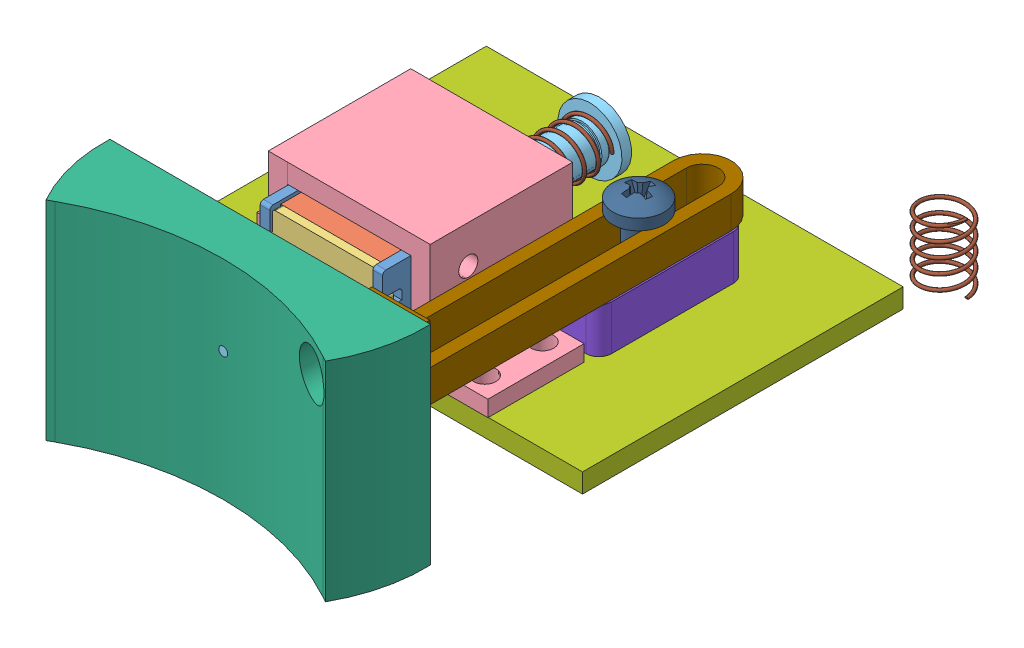
SolidWorks assembly solenoid assembly 2, configuration Default. Lengths in mm.
Overall size (70.84 33.54 84.51).
14 component instances, 11 part files, 14 mates.
Components (placement in the parent):
- solenoid assembly-1: solenoid assembly [Default] at (10.7886 26.9841 31.6501) size (43.25 18.9 29.35)
  - Solenoid frame-1: Solenoid frame [Default] at (12.0021 -4.2273 1.9322) size (19.1 15.9 29.35)
  - top face-2: top face [Default] at (3.3021 3.2227 1.0822) size (17.4 1.5 26.15)
  - top face-3: top face [Default] at (3.3021 -10.1773 1.0822) size (17.4 1.5 26.15)
  - Solenoid front frame-3: Solenoid front frame [Default] at (3.9521 -4.2292 15.4572) size (19.1 14.9 1.3)
  - mount solenoid-1: mount solenoid [Default] at (-5.7478 -4.2273 0.3372) x (0 0 1) z (-1 0 0) size (22.27 18.9 43.25)
- cylinder-1: cylinder [Default] at (15.8918 23.938 22.0581) x (0 0 1) z (-0.688665 0.72508 0) size (58.68 10 10)
- kicker-1: kicker [Default] at (14.7407 22.8447 56.3756) x (-1 0 0) z (0 1 0) size (50.03 13.18 32.5)
- testing board-1: testing board [Default] at (18.4884 11.8068 18.042) size (65 3 50)
- slider pole-2: slider pole [Default] at (32.2907 14.8068 15.298) size (10 7 23)
- slider-1: slider [Default] at (32.5307 21.8047 48.9015) x (0 0 -1) z (1 0 0) size (54.1 11.45 9)
- pan cross head screw_as-1: pan cross head screw_as [AS-NZS 1427 PC- M4 x 25-N] at (31.9907 29.9047 15.298) x (0 -1 0) z (-0.154373 0 0.988013) size (28.02 8 8)
- spring-1: spring [Default] at (14.7407 22.8447 16.5076) x (0.999856 -0.016979 0) z (0.016979 0.999856 0) size (7.76 11.37 8.66)
- spring-2: spring [Default] at (52.8173 13.6068 -11.5001) size (7.76 11.37 8.66)
Mates (geometry in assembly coordinates):
- Concentric1: concentric aligned: cylinder of solenoid assembly-1/Solenoid frame-1 through (14.7407 22.8447 19.6574) axis (0 0 -1) radius 3.175; cylinder of cylinder-1 through (14.7407 22.8447 5.6381) axis (0 0 -1) radius 3.175
- Concentric3: concentric aligned: cylinder of cylinder-1 through (14.7407 22.8447 42.614) axis (0 0 -1) radius 0.75; cylinder of kicker-1 through (14.7407 22.8447 68.6814) axis (0 0 -1) radius 0.7
- Parallel1: parallel anti-aligned: line of solenoid assembly-1/mount solenoid-1 through (5.0407 33.7068 43.0974) axis (1 0 0); line of kicker-1 through (39.7407 35.3447 55.5015) axis (-1 0 0)
- Tangent1: tangent anti-aligned: plane of cylinder-1 through (14.7407 22.8447 62.814) normal (0 0 1); cylinder of kicker-1 through (14.7407 10.3447 106.1689) axis (0 1 0) radius 43.3549
- Coincident4: coincident anti-aligned: plane of solenoid assembly-1/mount solenoid-1 through (27.2907 14.8068 43.0974) normal (0 -1 0); plane of testing board-1 through (18.4884 14.8068 18.042) normal (0 1 0)
- Coincident5: coincident anti-aligned: plane of testing board-1 through (18.4884 14.8068 18.042) normal (0 1 0); plane of slider pole-2 through (32.2907 14.8068 15.298) normal (0 -1 0)
- Coincident6: coincident anti-aligned: plane of solenoid assembly-1/mount solenoid-1 through (27.2907 22.7568 31.9874) normal (1 0 0); plane of slider pole-2 through (27.2907 21.8068 3.798) normal (-1 0 0)
- Concentric6: concentric anti-aligned: cylinder of kicker-1 through (32.5307 30.6047 55.5015) axis (0 0 1) radius 2; cylinder of slider-1 through (32.5307 30.6047 57.9015) axis (0 0 -1) radius 1.75
- Coincident7: coincident anti-aligned: plane of kicker-1 through (39.7407 35.3447 55.5015) normal (0 0 -1); plane of slider-1 through (28.0307 21.8047 55.5015) normal (0 0 1)
- Parallel2: parallel anti-aligned: line of kicker-1 through (39.7407 35.3447 55.5015) axis (-1 0 0); line of slider-1 through (28.0307 33.2547 52.9015) axis (1 0 0)
- Concentric7: concentric aligned: cylinder of slider pole-2 through (31.9907 11.8068 15.298) axis (0 1 0) radius 2.25; cylinder of pan cross head screw_as-1 through (31.9907 29.9047 15.298) axis (0 1 0) radius 2
- Coincident8: coincident anti-aligned: plane of slider-1 through (32.5307 26.8047 5.9015) normal (0 1 0); plane of pan cross head screw_as-1 through (33.9667 26.8047 15.6068) normal (0 -1 0)
- Coincident11: coincident anti-aligned: plane of cylinder-1 through (14.7407 22.8447 5.6381) normal (0 0 1); plane of spring-1 through (9.6679 18.6001 5.6381) normal (0 0 -1)
- Concentric9: concentric aligned: circle of cylinder-1; circle of spring-1
